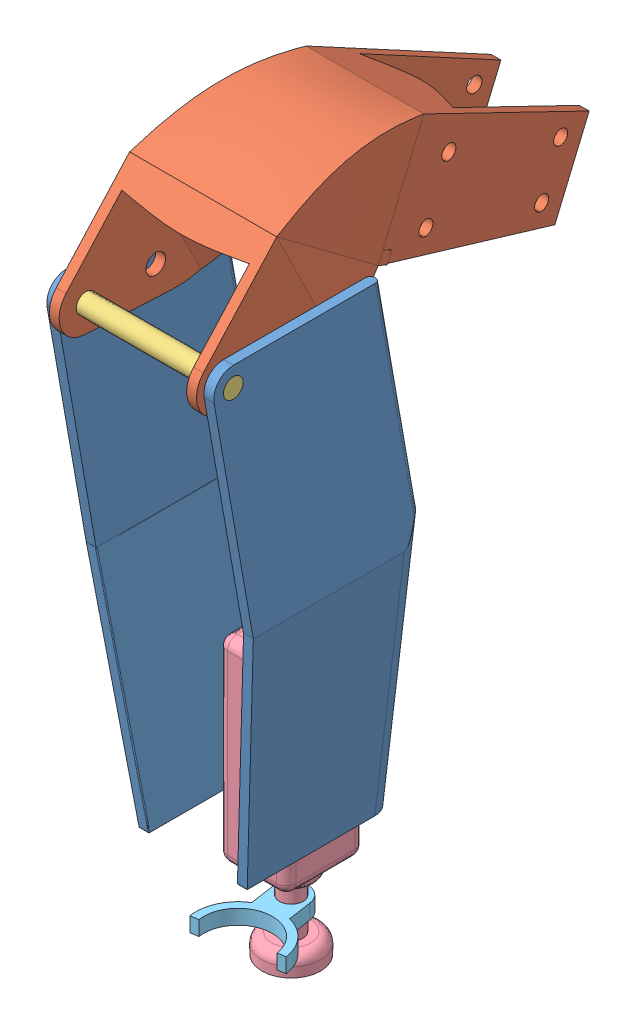
SolidWorks assembly Assembly, configuration Default. Lengths in mm.
Overall size (175.63 809.06 441.39).
11 component instances, 9 part files, 20 mates.
Components (placement in the parent):
- new bottom part-1: new bottom part [Default] at origin size (175.63 500 214.16)
- 2nd-2: 2nd [Default] at (-0.0728 498.689 -11.9803) x (0 -0.388855 -0.921299) z (1 0 0) size (383.22 227.14 156.58)
- part between top &bottom-1: part between top &bottom [Default] at (0.0728 431.1218 172.5231) size (170 20 20)
- Cylindrical bottom-1: Cylindrical bottom [Default] at (-20.2235 3.5514 0) size (70 285 80)
- Bottom Clamp-1: Bottom Clamp [Default] at (-0.0288 -142.5 39.9845) x (0.148571 0 0.988902) z (-0.988902 0 0.148571) size (81.6 15 86.46)
- hydraullic part 3-1: hydraullic part 3 [Default] at (0 196.3356 25.028) x (1 0 0) z (0 -0.002881 0.999996) size (50 238.69 57.9)
- piston 1-1: piston 1 [Default] at (0 406.3347 25.6329) x (1 0 0) z (0 0.002881 -0.999996) size (29.98 231.59 29.98)
- Part between haudralic and bottom-2: Part between haudralic and bottom [Default] at (0 186.6294 25) size (70 15 15)
- Part between botoom and bottom-1: Part between botoom and bottom [Default] at (0 0 35) size (20 20 90)
- Part between botoom and bottom-2: Part between botoom and bottom [Default] at (0 30 35) size (20 20 90)
- Part between botoom and bottom-3: Part between botoom and bottom [Default] at (0 60 35) size (20 20 90)
Mates (geometry in assembly coordinates):
- Coincident3: coordinate: point of new bottom part-1
- Concentric3: concentric anti-aligned: cylinder of new bottom part-1 through (113.3571 434.436 184.1619) axis (-1 0 0) radius 10; cylinder of 2nd-2 through (-78.3617 434.436 184.1619) axis (1 0 0) radius 10
- Hinge1: hinge anti-aligned: plane of 2nd-2; cylinder of 2nd-2 through (113.3571 434.436 184.1619) axis (-1 0 0) radius 10; plane of new bottom part-1 through (-75.0728 400.8345 63.7104) normal (-1 0 0); plane of new bottom part-1 through (-75.0728 434.436 184.1619) normal (1 0 0)
- Concentric4: concentric anti-aligned: cylinder of 2nd-2 through (-78.3617 434.436 184.1619) axis (1 0 0) radius 10; cylinder of part between top &bottom-1 through (85.0728 434.436 184.1619) axis (-1 0 0) radius 10
- Coincident4: coincident aligned: plane of new bottom part-1 through (85.0728 434.436 184.1619) normal (1 0 0); plane of part between top &bottom-1 through (85.0728 434.436 184.1619) normal (1 0 0)
- Coincident6: coincident anti-aligned: plane of new bottom part-1 through (0 0 0) normal (0 0 1); plane of Cylindrical bottom-1 through (-20.2235 3.5514 0) normal (0 0 -1)
- Concentric5: concentric anti-aligned: cylinder of new bottom part-1 through (0 30 176) axis (0 0 -1) radius 10; cylinder of Cylindrical bottom-1 through (0 30 0) axis (0 0 1) radius 10
- Concentric6: concentric anti-aligned: cylinder of Cylindrical bottom-1 through (-0.0288 -160 39.9845) axis (0 1 0) radius 12; cylinder of Bottom Clamp-1 through (-0.0288 -127.5 39.9845) axis (0 -1 0) radius 12
- Width4: width anti-aligned: plane of Cylindrical bottom-1 through (0 -110 40) normal (0 -1 0); plane of Bottom Clamp-1 through (-0.0288 -160 39.9845) normal (0 1 0); plane of Cylindrical bottom-1 through (-0.0288 -127.5 39.9845) normal (0 1 0); plane of Bottom Clamp-1 through (-0.0288 -142.5 39.9845) normal (0 -1 0)
- Concentric7: concentric anti-aligned: cylinder of new bottom part-1 through (0 0 176) axis (0 0 -1) radius 10; cylinder of Cylindrical bottom-1 through (0 0 0) axis (0 0 1) radius 10
- Coincident9: coincident anti-aligned: plane of new bottom part-1 through (25 201.6294 40) normal (-1 0 0); plane of hydraullic part 3-1 through (25 186.6294 25.0322) normal (1 0 0)
- Concentric8: concentric aligned: cylinder of new bottom part-1 through (-56.2132 186.6294 25) axis (1 0 0) radius 7.5; cylinder of hydraullic part 3-1 through (-25 186.6294 25) axis (1 0 0) radius 7.5
- Concentric23: concentric anti-aligned: cylinder of hydraullic part 3-1 through (0 396.3348 25.6041) axis (0 -0.999996 -0.002881) radius 15; cylinder of piston 1-1 through (0 206.3355 25.0568) axis (0 0.999996 0.002881) radius 14.9897
- Concentric24: concentric anti-aligned: cylinder of 2nd-2 through (46.1404 422.3229 25.6789) axis (-1 0 0) radius 7.5; cylinder of piston 1-1 through (-12.5 422.3229 25.6789) axis (1 0 0) radius 9.9852
- LimitDistance1: limit distance = 10 mm anti-aligned: plane of hydraullic part 3-1 through (-25 196.4188 -3.8558) normal (0 0.999996 0.002881); plane of piston 1-1 through (0 206.3355 25.0568) normal (0 -0.999996 -0.002881)
- LimitAngle3: limit planar angle = 0.050323 rad anti-aligned: plane of new bottom part-1 through (-75.0728 454.436 34.4003) normal (0 1 0); plane of 2nd-2 through (-0.0728 397.2795 -6.8727) normal (0 -0.998734 0.050302)
- Concentric25: concentric anti-aligned: cylinder of new bottom part-1 through (-56.2132 186.6294 25) axis (1 0 0) radius 7.5; cylinder of Part between haudralic and bottom-2 through (35 186.6294 25) axis (-1 0 0) radius 7.5
- Coincident25: coincident aligned: plane of new bottom part-1 through (35 201.6294 40) normal (1 0 0); plane of Part between haudralic and bottom-2 through (35 186.6294 25) normal (1 0 0)
- Coincident26: coincident aligned: plane of Cylindrical bottom-1 through (-20.2235 3.5514 80) normal (0 0 1); plane of Part between botoom and bottom-1 through (0 0 80) normal (0 0 1)
- Concentric27: concentric anti-aligned: cylinder of Cylindrical bottom-1 through (0 0 0) axis (0 0 1) radius 10; cylinder of Part between botoom and bottom-1 through (0 0 80) axis (0 0 -1) radius 10
